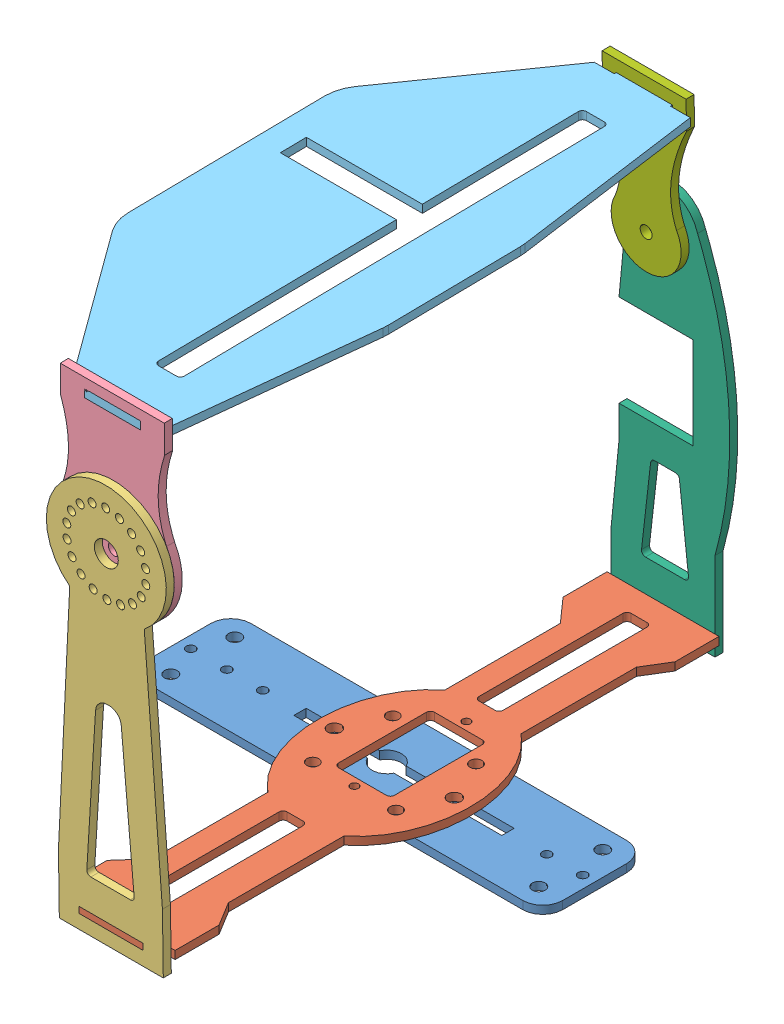
SolidWorks assembly suporte_camera_montagem, configuration Valor predeterminado. Lengths in mm.
Overall size (104 122.46 141.42).
7 component instances, 7 part files, 18 mates.
Components (placement in the parent):
- Peça1-1: Peça1 [Valor predeterminado] at (11.8384 18.378 130) size (104 2 26)
- Peça2-1: Peça2 [Valor predeterminado] at (15.0253 20.378 131.2803) x (0 0 -1) z (1 0 0) size (140 2 38)
- Peça5-1: Peça5 [Valor predeterminado] at (14.1892 102.8692 202.4806) x (0 0.01455 -0.999894) z (1 0 0) size (2 101 30)
- Peça4-1: Peça4 [Valor predeterminado] at (14.1892 102.9274 198.4811) x (0 -0.01455 0.999894) z (-1 -0.000316 -0.000005) size (2 49 30)
- Peça3-1: Peça3 [Valor predeterminado] at (-1.5106 133.3445 133.4167) x (0 -0.01455 0.999894) z (-1 -0.000316 -0.000005) size (135 2 57)
- Peça8-suporte_camera-1: Peça8-suporte_camera [Valor predeterminado] at (14.1892 104.448 61.2803) x (0 1 0) z (0 0 1) size (96.07 31.37 2)
- Peça7-suporte_camera-1: Peça7-suporte_camera [Valor predeterminado] at (14.1891 105.0555 67.4982) x (0 0.01455 -0.999894) z (1 0.000316 0.000005) size (2 43 21)
Mates (geometry in assembly coordinates):
- Coincidente1: coincident anti-aligned: plane of Peça1-1 through (58.8384 20.378 122) normal (0 1 0); plane of Peça2-1 through (15.0253 20.378 131.2803) normal (0 -1 0)
- Paralelo1: parallel anti-aligned: line of Peça1-1 through (-40.1616 20.378 122) axis (0 0 1); line of Peça2-1 through (24.5253 20.378 182.2803) axis (0 0 -1)
- Bloquear1: lock: unknown of Peça1-1; unknown of Peça2-1
- Coincidente4: coincident: point of Peça2-1; plane of Peça5-1 through (22.1892 20.378 201.2803) normal (0 0.999894 0.01455)
- Coincidente5: coincident anti-aligned: line of Peça2-1 through (6.1892 20.378 201.2803) axis (1 0 0); line of Peça5-1 through (22.1892 20.378 201.2803) axis (-1 0 0)
- Coincidente6: coincident anti-aligned: plane of Peça2-1 through (22.1892 22.378 199.2803) normal (1 0 0); plane of Peça5-1 through (22.1892 21.9392 201.303) normal (-1 0 0)
- Coincidente12: coincident anti-aligned: line of Peça2-1 through (22.1892 20.378 61.2803) axis (-1 0 0); line of Peça8-suporte_camera-1 through (6.1892 20.378 61.2803) axis (1 0 0)
- Coincidente13: coincident aligned: line of Peça2-1 through (22.1892 22.378 61.2803) axis (-1 0 0); line of Peça8-suporte_camera-1 through (22.1892 22.378 61.2803) axis (-1 0 0)
- Coincidente14: coincident anti-aligned: plane of Peça2-1 through (6.1892 22.378 63.2803) normal (-1 0 0); plane of Peça8-suporte_camera-1 through (6.1892 20.378 63.2803) normal (1 0 0)
- Paralelo5: parallel aligned: plane of Peça3-1 through (7.1792 136.3291 65.953) normal (0 0.01455 -0.999894); plane of Peça7-suporte_camera-1 through (20.6632 119.5693 65.7092) normal (0 0.01455 -0.999894)
- Coincidente47: coincident: line of Peça3-1 through (21.1799 134.3337 65.924) axis (-1 -0.000316 -0.000005); plane of Peça7-suporte_camera-1 through (21.1799 134.3046 67.9238) normal (-0.000316 0.999894 0.01455)
- Coincidente48: coincident anti-aligned: plane of Peça3-1 through (21.1792 136.3335 65.9531) normal (1 0.000316 0.000005); plane of Peça7-suporte_camera-1 through (21.1792 136.3044 67.9529) normal (-1 -0.000316 -0.000005)
- Coincidente50: coincident: plane of Peça4-1 through (7.1799 132.3942 198.9098) normal (-0.000316 0.999894 0.01455); line of Peça3-1 through (21.1799 132.3695 200.9097) axis (-1 -0.000316 -0.000005)
- Coincidente51: coincident anti-aligned: plane of Peça4-1 through (7.1794 133.9219 198.9321) normal (1 0.000316 0.000005); plane of Peça3-1 through (7.1792 134.4013 198.439) normal (-1 -0.000316 -0.000005)
- Concêntrico4: concentric anti-aligned: circle of Peça5-1; circle of Peça4-1
- Coincidente53: coincident aligned: plane of Peça4-1 through (2.9633 119.5562 200.7233) normal (0 -0.01455 0.999894); plane of Peça3-1 through (7.1792 134.3649 200.9387) normal (0 -0.01455 0.999894)
- Coincidente55: coincident aligned: plane of Peça3-1 through (7.1792 136.3291 65.953) normal (0 0.01455 -0.999894); plane of Peça7-suporte_camera-1 through (20.6632 119.5693 65.7092) normal (0 0.01455 -0.999894)
- Coincidente56: coincident anti-aligned: plane of Peça5-1 through (14.1892 102.8983 200.4809) normal (0 0.01455 -0.999894); plane of Peça4-1 through (2.9633 119.5562 200.7233) normal (0 -0.01455 0.999894)
